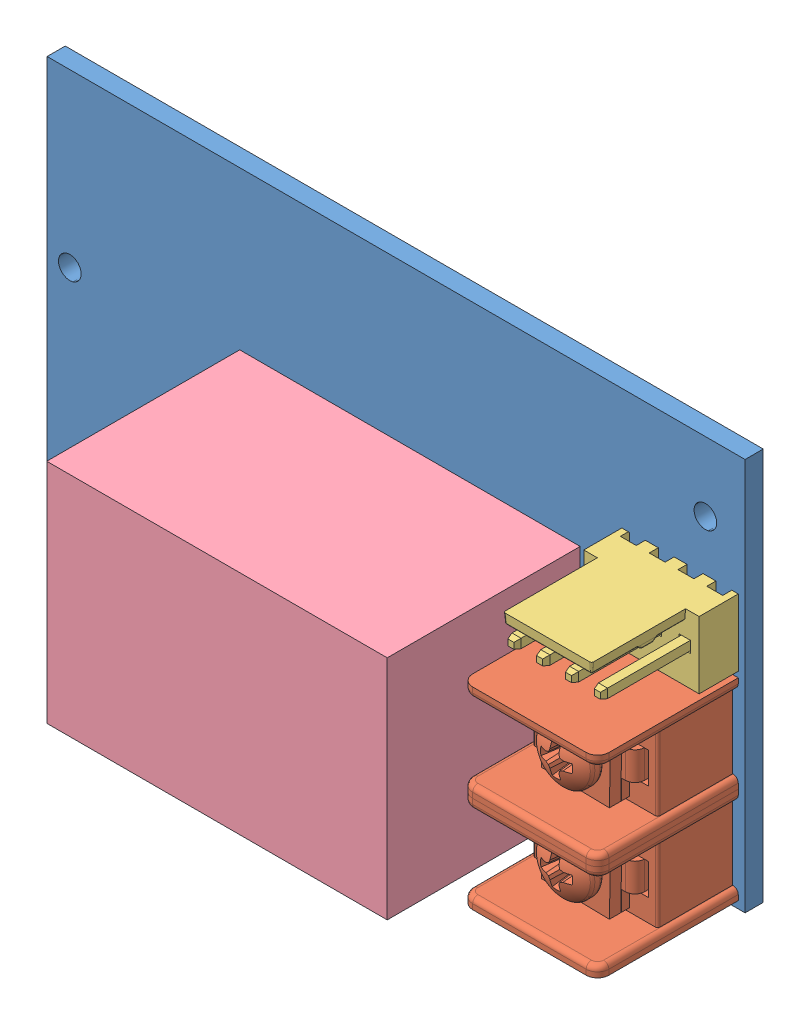
SolidWorks assembly board_asemb, configuration Default. Lengths in mm.
Overall size (61.5 34.6 20.85).
4 component instances, 4 part files, 11 mates.
Components (placement in the parent):
- board-1: board [Default] at (0.4354 12.4637 43.6474) size (61.5 34.6 1.6)
- KF8500-2P-1: KF8500-2P [Default] at (55.37 41.0744 40.3478) x (1 0 0) z (0 -1 0) size (12 16.25 17)
- User Library-WF-4-1: User Library-WF-4 [Default] at (56.2554 33.8037 45.2474) x (1 0 0) z (0 -1 0) size (10.16 14.28 5.9)
- pcb-1: pcb [Default] at (17.4054 13.1637 45.2474) size (30 20 17)
Mates (geometry in assembly coordinates):
- Coincident1: coincident anti-aligned: plane of board-1 through (0.4354 12.4637 45.2474) normal (0 0 1); plane of KF8500-2P-1 through (49.3354 14.0287 45.2474) normal (0 0 -1)
- Parallel1: parallel aligned: plane of board-1 through (0.4354 12.4637 45.2474) normal (0 -1 0); plane of KF8500-2P-1 through (60.3354 13.1037 56.6474) normal (0 -1 0)
- Distance1: distance = 0.6 mm aligned: plane of KF8500-2P-1 through (61.3354 22.5287 45.2474) normal (1 0 0); plane of board-1 through (61.9354 12.4637 45.2474) normal (1 0 0)
- Distance2: distance = 0.64 mm aligned: plane of KF8500-2P-1 through (60.3354 13.1037 56.6474) normal (0 -1 0); plane of board-1 through (0.4354 12.4637 45.2474) normal (0 -1 0)
- Coincident5: coincident anti-aligned: plane of board-1 through (0.4354 12.4637 45.2474) normal (0 0 1); plane of User Library-WF-4-1 through (56.2554 33.8037 45.2474) normal (0 0 -1)
- Parallel3: parallel aligned: plane of board-1 through (0.4354 47.0637 45.2474) normal (0 1 0); plane of User Library-WF-4-1 through (51.1754 36.5037 48.6974) normal (0 1 0)
- Coincident8: coincident aligned: plane of KF8500-2P-1 through (61.3354 29.1787 45.2474) normal (1 0 0); plane of User Library-WF-4-1 through (61.3354 36.5037 48.6974) normal (1 0 0)
- Distance3: distance = 0.5 mm anti-aligned: plane of User Library-WF-4-1 through (51.1754 30.6037 48.6974) normal (0 -1 0); plane of KF8500-2P-1 through (50.3354 30.1037 56.6474) normal (0 1 0)
- Coincident9: coincident anti-aligned: plane of board-1 through (0.4354 12.4637 45.2474) normal (0 0 1); plane of pcb-1 through (17.4054 13.1637 45.2474) normal (0 0 -1)
- Distance4: distance = 0.7 mm aligned: plane of pcb-1 through (17.4054 13.1637 62.2474) normal (0 -1 0); plane of board-1 through (0.4354 12.4637 45.2474) normal (0 -1 0)
- Distance5: distance = 14.53 mm aligned: plane of pcb-1 through (47.4054 13.1637 62.2474) normal (1 0 0); plane of board-1 through (61.9354 12.4637 45.2474) normal (1 0 0)
